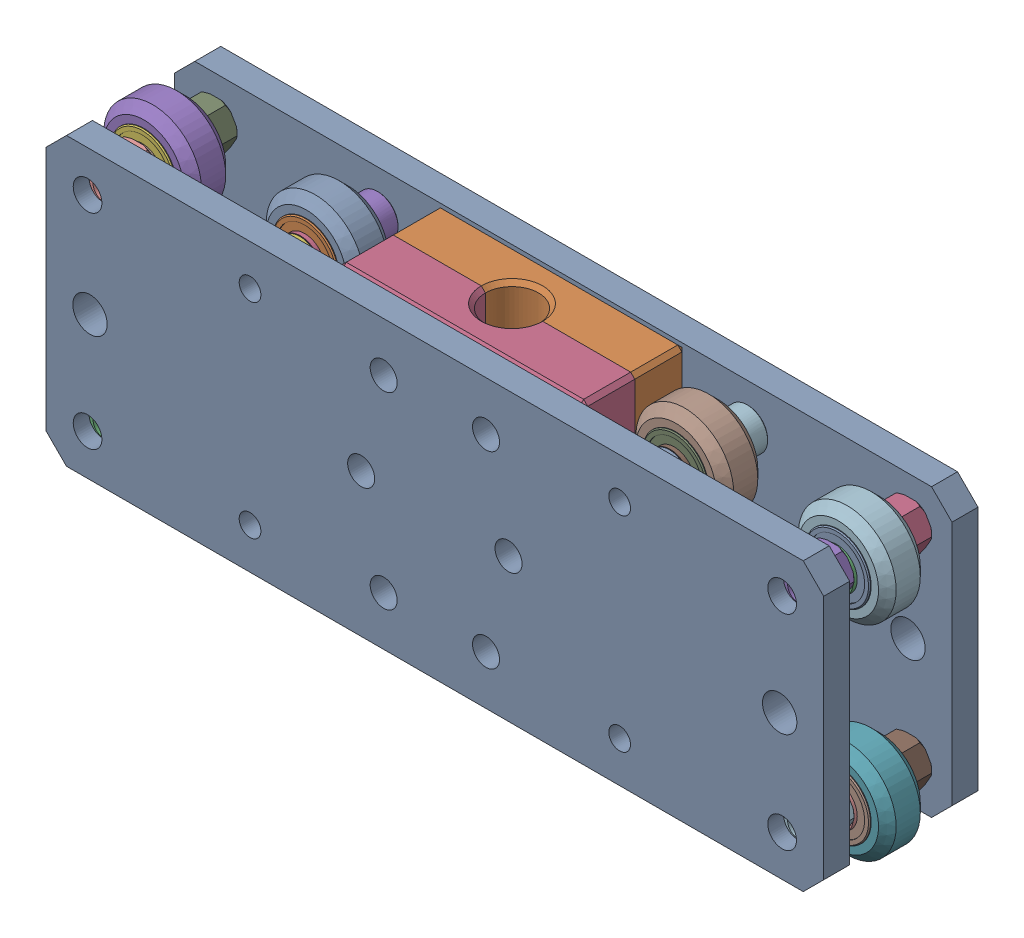
SolidWorks assembly Trim Sled Assembly, configuration Default. Lengths in mm.
Overall size (193.6 74.69 37.7).
86 component instances, 8 part files, 0 mates.
Components (placement in the parent):
- Trim Sled Plate-1: Trim Sled Plate [Default] at origin size (190 70 6.35)
- Lead Screw Nut Assembly-1: Lead Screw Nut Assembly [Default] at origin size (60 70 25)
  - Lead Screw Nut Clamshell-1: Lead Screw Nut Clamshell [Default] at origin size (60 70 12.5)
  - MISUMI Brass Lead Screw Flange Nut - MTSGR12-1: MISUMI Brass Lead Screw Flange Nut - MTSGR12 [Default] at (0 -15 30) x (0 1 0) z (0 0 1) size (30 44 24)
  - Lead Screw Nut Clamshell-2: Lead Screw Nut Clamshell [Default] at (0 0 60) x (-1 0 0) z (0 0 -1) size (60 70 12.5)
- Inboard Wheel Stack-1: Inboard Wheel Stack [Default] at (-45.15 -25 23.5) size (23.9 23.9 25)
  - Xtreme Solid V Wheel Kit Assembly-1: Xtreme Solid V Wheel Kit Assembly [Default] at origin size (23.9 23.9 13)
    - Precision Shim - 10x5x1mm-1: Precision Shim - 10x5x1mm [Default] at origin size (10 10 1)
    - Xtreme Solid V Wheel Assembly-1: Xtreme Solid V Wheel Assembly [Default] at (45.15 25 -23.5) size (23.9 23.9 11)
      - Xtreme Solid V Wheel-1: Xtreme Solid V Wheel [Default] at (-45.15 -25 30) x (0 0 1) z (-1 0 0) size (10.2 23.9 23.9)
      - Wheel+Kit+-+5x16x5mm+Sealed+Radial+Ball+Bearing.step.f3d-1: Wheel+Kit+-+5x16x5mm+Sealed+Radial+Ball+Bearing.step.f3d [Default] at (-45.15 -25 30) x (0 1 0) z (-1 0 0) size (16 5 16)
      - Wheel+Kit+-+5x16x5mm+Sealed+Radial+Ball+Bearing.step.f3d-2: Wheel+Kit+-+5x16x5mm+Sealed+Radial+Ball+Bearing.step.f3d [Default] at (-45.15 -25 30) x (0 1 0) z (1 0 0) size (16 5 16)
    - Precision Shim - 10x5x1mm-2: Precision Shim - 10x5x1mm [Default] at (0 0 12) size (10 10 1)
  - Aluminum Spacer 6mm-1: Aluminum Spacer 6mm [Default] at (0 0 -6) size (10 10 6)
  - Aluminum Spacer 6mm-2: Aluminum Spacer 6mm [Default] at (0 0 13) size (10 10 6)
- Inboard Wheel Stack_1-1: Inboard Wheel Stack_1 [Default] at (-45.15 25 23.5) size (23.9 23.9 25)
  - Xtreme Solid V Wheel Kit Assembly_1-1: Xtreme Solid V Wheel Kit Assembly_1 [Default] at origin size (23.9 23.9 13)
    - Precision Shim - 10x5x1mm-1: Precision Shim - 10x5x1mm [Default] at origin size (10 10 1)
    - Xtreme Solid V Wheel Assembly_1-1: Xtreme Solid V Wheel Assembly_1 [Default] at (45.15 55 -23.5) size (23.9 23.9 11)
      - Xtreme Solid V Wheel-1: Xtreme Solid V Wheel [Default] at (-45.15 -55 30) x (0 0 1) z (-1 0 0) size (10.2 23.9 23.9)
      - Wheel+Kit+-+5x16x5mm+Sealed+Radial+Ball+Bearing.step.f3d-1: Wheel+Kit+-+5x16x5mm+Sealed+Radial+Ball+Bearing.step.f3d [Default] at (-45.15 -55 30) x (0 1 0) z (-1 0 0) size (16 5 16)
      - Wheel+Kit+-+5x16x5mm+Sealed+Radial+Ball+Bearing.step.f3d-2: Wheel+Kit+-+5x16x5mm+Sealed+Radial+Ball+Bearing.step.f3d [Default] at (-45.15 -55 30) x (0 1 0) z (1 0 0) size (16 5 16)
    - Precision Shim - 10x5x1mm-2: Precision Shim - 10x5x1mm [Default] at (0 0 12) size (10 10 1)
  - Aluminum Spacer 6mm-1: Aluminum Spacer 6mm [Default] at (0 0 -6) size (10 10 6)
  - Aluminum Spacer 6mm-2: Aluminum Spacer 6mm [Default] at (0 0 13) size (10 10 6)
- Inboard Wheel Stack_2-1: Inboard Wheel Stack_2 [Default] at (45.15 25 23.5) size (23.9 23.9 25)
  - Xtreme Solid V Wheel Kit Assembly_2-1: Xtreme Solid V Wheel Kit Assembly_2 [Default] at origin size (23.9 23.9 13)
    - Precision Shim - 10x5x1mm-1: Precision Shim - 10x5x1mm [Default] at origin size (10 10 1)
    - Xtreme Solid V Wheel Assembly_2-1: Xtreme Solid V Wheel Assembly_2 [Default] at (154.85 55 -23.5) size (23.9 23.9 11)
      - Xtreme Solid V Wheel-1: Xtreme Solid V Wheel [Default] at (-154.85 -55 30) x (0 0 1) z (-1 0 0) size (10.2 23.9 23.9)
      - Wheel+Kit+-+5x16x5mm+Sealed+Radial+Ball+Bearing.step.f3d-1: Wheel+Kit+-+5x16x5mm+Sealed+Radial+Ball+Bearing.step.f3d [Default] at (-154.85 -55 30) x (0 1 0) z (-1 0 0) size (16 5 16)
      - Wheel+Kit+-+5x16x5mm+Sealed+Radial+Ball+Bearing.step.f3d-2: Wheel+Kit+-+5x16x5mm+Sealed+Radial+Ball+Bearing.step.f3d [Default] at (-154.85 -55 30) x (0 1 0) z (1 0 0) size (16 5 16)
    - Precision Shim - 10x5x1mm-2: Precision Shim - 10x5x1mm [Default] at (0 0 12) size (10 10 1)
  - Aluminum Spacer 6mm-1: Aluminum Spacer 6mm [Default] at (0 0 -6) size (10 10 6)
  - Aluminum Spacer 6mm-2: Aluminum Spacer 6mm [Default] at (0 0 13) size (10 10 6)
- Inboard Wheel Stack_3-1: Inboard Wheel Stack_3 [Default] at (45.15 -25 23.5) size (23.9 23.9 25)
  - Xtreme Solid V Wheel Kit Assembly_3-1: Xtreme Solid V Wheel Kit Assembly_3 [Default] at origin size (23.9 23.9 13)
    - Precision Shim - 10x5x1mm-1: Precision Shim - 10x5x1mm [Default] at origin size (10 10 1)
    - Xtreme Solid V Wheel Assembly_3-1: Xtreme Solid V Wheel Assembly_3 [Default] at (154.85 25 -23.5) size (23.9 23.9 11)
      - Xtreme Solid V Wheel-1: Xtreme Solid V Wheel [Default] at (-154.85 -25 30) x (0 0 1) z (-1 0 0) size (10.2 23.9 23.9)
      - Wheel+Kit+-+5x16x5mm+Sealed+Radial+Ball+Bearing.step.f3d-1: Wheel+Kit+-+5x16x5mm+Sealed+Radial+Ball+Bearing.step.f3d [Default] at (-154.85 -25 30) x (0 1 0) z (-1 0 0) size (16 5 16)
      - Wheel+Kit+-+5x16x5mm+Sealed+Radial+Ball+Bearing.step.f3d-2: Wheel+Kit+-+5x16x5mm+Sealed+Radial+Ball+Bearing.step.f3d [Default] at (-154.85 -25 30) x (0 1 0) z (1 0 0) size (16 5 16)
    - Precision Shim - 10x5x1mm-2: Precision Shim - 10x5x1mm [Default] at (0 0 12) size (10 10 1)
  - Aluminum Spacer 6mm-1: Aluminum Spacer 6mm [Default] at (0 0 -6) size (10 10 6)
  - Aluminum Spacer 6mm-2: Aluminum Spacer 6mm [Default] at (0 0 13) size (10 10 6)
- Outboard Wheel Stack-1: Outboard Wheel Stack [Default] at (-84.85 -25.79 23.5) size (23.9 23.9 30)
  - Xtreme Solid V Wheel Kit Assembly_4-1: Xtreme Solid V Wheel Kit Assembly_4 [Default] at origin size (23.9 23.9 13)
    - Precision Shim - 10x5x1mm-1: Precision Shim - 10x5x1mm [Default] at origin size (10 10 1)
    - Xtreme Solid V Wheel Assembly_4-1: Xtreme Solid V Wheel Assembly_4 [Default] at (84.85 25.79 -23.5) size (23.9 23.9 11)
      - Xtreme Solid V Wheel-1: Xtreme Solid V Wheel [Default] at (-84.85 -25.79 30) x (0 0 1) z (-1 0 0) size (10.2 23.9 23.9)
      - Wheel+Kit+-+5x16x5mm+Sealed+Radial+Ball+Bearing.step.f3d-1: Wheel+Kit+-+5x16x5mm+Sealed+Radial+Ball+Bearing.step.f3d [Default] at (-84.85 -25.79 30) x (0 1 0) z (-1 0 0) size (16 5 16)
      - Wheel+Kit+-+5x16x5mm+Sealed+Radial+Ball+Bearing.step.f3d-2: Wheel+Kit+-+5x16x5mm+Sealed+Radial+Ball+Bearing.step.f3d [Default] at (-84.85 -25.79 30) x (0 1 0) z (1 0 0) size (16 5 16)
    - Precision Shim - 10x5x1mm-2: Precision Shim - 10x5x1mm [Default] at (0 0 12) size (10 10 1)
  - Eccentric Spacer 6mm-1: Eccentric Spacer 6mm [Default] at (0 0.79 -6) x (1 0 0) z (0 -1 0) size (11.55 8.5 10)
  - Eccentric Spacer 6mm-2: Eccentric Spacer 6mm [Default] at (0 0.79 19) x (-1 0 0) z (0 -1 0) size (11.55 8.5 10)
- Outboard Wheel Stack_1-1: Outboard Wheel Stack_1 [Default] at (-84.85 24.21 23.5) size (23.9 23.9 30)
  - Xtreme Solid V Wheel Kit Assembly_5-1: Xtreme Solid V Wheel Kit Assembly_5 [Default] at origin size (23.9 23.9 13)
    - Precision Shim - 10x5x1mm-1: Precision Shim - 10x5x1mm [Default] at origin size (10 10 1)
    - Xtreme Solid V Wheel Assembly_5-1: Xtreme Solid V Wheel Assembly_5 [Default] at (84.85 55.79 -23.5) size (23.9 23.9 11)
      - Xtreme Solid V Wheel-1: Xtreme Solid V Wheel [Default] at (-84.85 -55.79 30) x (0 0 1) z (-1 0 0) size (10.2 23.9 23.9)
      - Wheel+Kit+-+5x16x5mm+Sealed+Radial+Ball+Bearing.step.f3d-1: Wheel+Kit+-+5x16x5mm+Sealed+Radial+Ball+Bearing.step.f3d [Default] at (-84.85 -55.79 30) x (0 1 0) z (-1 0 0) size (16 5 16)
      - Wheel+Kit+-+5x16x5mm+Sealed+Radial+Ball+Bearing.step.f3d-2: Wheel+Kit+-+5x16x5mm+Sealed+Radial+Ball+Bearing.step.f3d [Default] at (-84.85 -55.79 30) x (0 1 0) z (1 0 0) size (16 5 16)
    - Precision Shim - 10x5x1mm-2: Precision Shim - 10x5x1mm [Default] at (0 0 12) size (10 10 1)
  - Eccentric Spacer 6mm-1: Eccentric Spacer 6mm [Default] at (0 0.79 -6) x (1 0 0) z (0 -1 0) size (11.55 8.5 10)
  - Eccentric Spacer 6mm-2: Eccentric Spacer 6mm [Default] at (0 0.79 19) x (-1 0 0) z (0 -1 0) size (11.55 8.5 10)
- Outboard Wheel Stack_2-1: Outboard Wheel Stack_2 [Default] at (84.85 24.21 23.5) size (23.9 23.9 30)
  - Xtreme Solid V Wheel Kit Assembly_6-1: Xtreme Solid V Wheel Kit Assembly_6 [Default] at origin size (23.9 23.9 13)
    - Precision Shim - 10x5x1mm-1: Precision Shim - 10x5x1mm [Default] at origin size (10 10 1)
    - Xtreme Solid V Wheel Assembly_6-1: Xtreme Solid V Wheel Assembly_6 [Default] at (115.15 55.79 -23.5) size (23.9 23.9 11)
      - Xtreme Solid V Wheel-1: Xtreme Solid V Wheel [Default] at (-115.15 -55.79 30) x (0 0 1) z (-1 0 0) size (10.2 23.9 23.9)
      - Wheel+Kit+-+5x16x5mm+Sealed+Radial+Ball+Bearing.step.f3d-1: Wheel+Kit+-+5x16x5mm+Sealed+Radial+Ball+Bearing.step.f3d [Default] at (-115.15 -55.79 30) x (0 1 0) z (-1 0 0) size (16 5 16)
      - Wheel+Kit+-+5x16x5mm+Sealed+Radial+Ball+Bearing.step.f3d-2: Wheel+Kit+-+5x16x5mm+Sealed+Radial+Ball+Bearing.step.f3d [Default] at (-115.15 -55.79 30) x (0 1 0) z (1 0 0) size (16 5 16)
    - Precision Shim - 10x5x1mm-2: Precision Shim - 10x5x1mm [Default] at (0 0 12) size (10 10 1)
  - Eccentric Spacer 6mm-1: Eccentric Spacer 6mm [Default] at (0 0.79 -6) x (1 0 0) z (0 -1 0) size (11.55 8.5 10)
  - Eccentric Spacer 6mm-2: Eccentric Spacer 6mm [Default] at (0 0.79 19) x (-1 0 0) z (0 -1 0) size (11.55 8.5 10)
- Outboard Wheel Stack_3-1: Outboard Wheel Stack_3 [Default] at (84.85 -25.79 23.5) size (23.9 23.9 30)
  - Xtreme Solid V Wheel Kit Assembly_7-1: Xtreme Solid V Wheel Kit Assembly_7 [Default] at origin size (23.9 23.9 13)
    - Precision Shim - 10x5x1mm-1: Precision Shim - 10x5x1mm [Default] at origin size (10 10 1)
    - Xtreme Solid V Wheel Assembly_7-1: Xtreme Solid V Wheel Assembly_7 [Default] at (115.15 25.79 -23.5) size (23.9 23.9 11)
      - Xtreme Solid V Wheel-1: Xtreme Solid V Wheel [Default] at (-115.15 -25.79 30) x (0 0 1) z (-1 0 0) size (10.2 23.9 23.9)
      - Wheel+Kit+-+5x16x5mm+Sealed+Radial+Ball+Bearing.step.f3d-1: Wheel+Kit+-+5x16x5mm+Sealed+Radial+Ball+Bearing.step.f3d [Default] at (-115.15 -25.79 30) x (0 1 0) z (-1 0 0) size (16 5 16)
      - Wheel+Kit+-+5x16x5mm+Sealed+Radial+Ball+Bearing.step.f3d-2: Wheel+Kit+-+5x16x5mm+Sealed+Radial+Ball+Bearing.step.f3d [Default] at (-115.15 -25.79 30) x (0 1 0) z (1 0 0) size (16 5 16)
    - Precision Shim - 10x5x1mm-2: Precision Shim - 10x5x1mm [Default] at (0 0 12) size (10 10 1)
  - Eccentric Spacer 6mm-1: Eccentric Spacer 6mm [Default] at (0 0.79 -6) x (1 0 0) z (0 -1 0) size (11.55 8.5 10)
  - Eccentric Spacer 6mm-2: Eccentric Spacer 6mm [Default] at (0 0.79 19) x (-1 0 0) z (0 -1 0) size (11.55 8.5 10)
- Trim Sled Plate-2: Trim Sled Plate [Default] at (0 0 31.35) size (190 70 6.35)
